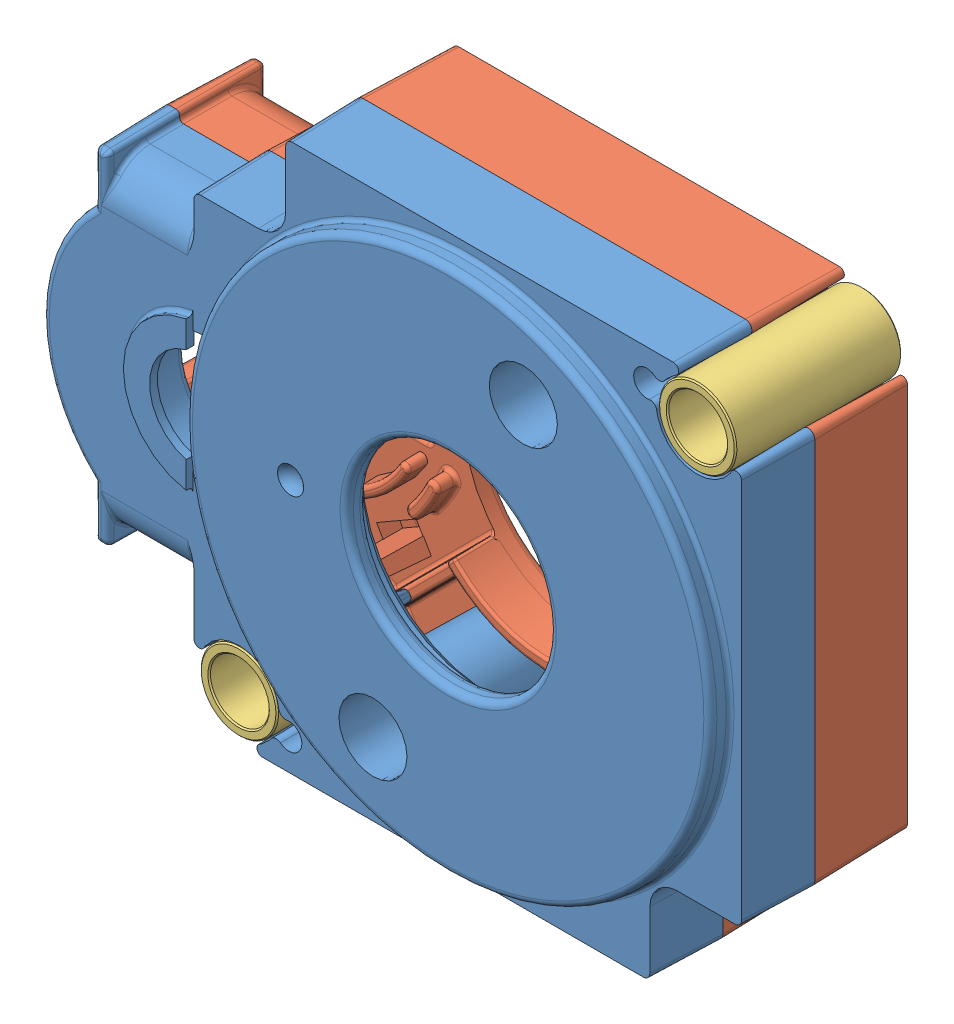
SolidWorks assembly VersaPlanetary_Integrated_Encoder_217-5046, configuration Default. Lengths in mm.
Overall size (54.08 43.13 14.62).
4 component instances, 3 part files, 6 mates.
Components (placement in the parent):
- 217-4783-001 Rev3-1: 217-4783-001 Rev3 [Default] at (1.6416 -5.4471 70.4351) size (53.55 42 11.11)
- 217-4783-002 Rev7_Sealed Config-1: 217-4783-002 Rev7_Sealed Config [Default] at (1.6416 -5.4471 60.4851) x (0 1 0) z (0 0 1) size (42 51.56 9.32)
- 217-4783-006 Rev3-1: 217-4783-006 Rev3 [Default] at (19.1416 12.0529 66.8351) x (-0.867641 0.497191 0) z (0 0 1) size (5.9 5.9 12.7)
- 217-4783-006 Rev3-2: 217-4783-006 Rev3 [Default] at (-15.8584 -22.9471 66.8351) x (0.825154 -0.564908 0) z (0 0 1) size (5.9 5.9 12.7)
Mates (geometry in assembly coordinates):
- Concentric1: concentric anti-aligned: cone of 217-4783-001 Rev3-1 through (-15.8584 -22.9471 73.1851) axis (0 0 -1); cylinder of 217-4783-006 Rev3-2 through (-15.8584 -22.9471 74.2112) axis (0 0 1) radius 2.95
- Concentric2: concentric aligned: cone of 217-4783-002 Rev7_Sealed Config-1 through (-15.8584 -22.9471 60.4851) axis (0 0 1); cylinder of 217-4783-006 Rev3-2 through (-15.8584 -22.9471 74.2112) axis (0 0 1) radius 2.95
- Coincident3: coincident anti-aligned: plane of 217-4783-001 Rev3-1 through (1.6416 -5.4471 67.6851) normal (0 0 -1); plane of 217-4783-002 Rev7_Sealed Config-1 through (1.6416 -5.4471 67.6851) normal (0 0 1)
- Concentric3: concentric aligned: circle of 217-4783-001 Rev3-1; cylinder of 217-4783-006 Rev3-1 through (19.1416 12.0529 74.2112) axis (0 0 1) radius 2.95
- Coincident4: coincident aligned: plane of 217-4783-002 Rev7_Sealed Config-1 through (1.6416 -5.4471 60.4851) normal (0 0 -1); plane of 217-4783-006 Rev3-1 through (17.6749 9.4934 60.4851) normal (0 0 -1)
- Coincident5: coincident aligned: plane of 217-4783-002 Rev7_Sealed Config-1 through (1.6416 -5.4471 60.4851) normal (0 0 -1); plane of 217-4783-006 Rev3-2 through (-14.1919 -20.5129 60.4851) normal (0 0 -1)
